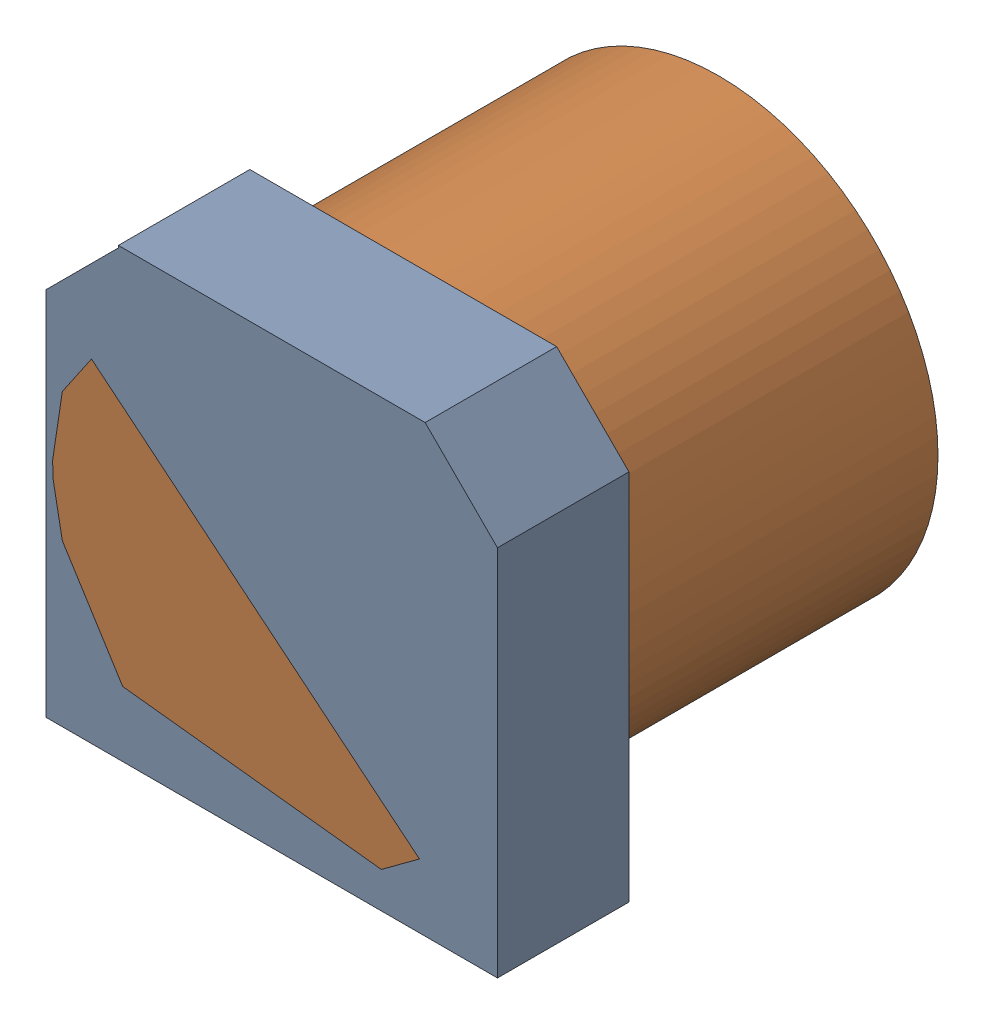
SolidWorks assembly C16, configuration Default. Lengths in mm.
Overall size (10.3 10.15 10.2).
4 component instances, 2 part files, 0 mates.
Components (placement in the parent):
- 402660496-1: 402660496 [Default] at (48.768 65.457 -4.1024) size (10.3 10.15 3)
  - Extruded_10-1: Extruded_10 [Default] at origin size (10.3 10.15 3)
- 405594336-1: 405594336 [Default] at (48.7681 65.5319 -1.1024) x (1 0 0) z (0 0 -1) size (10 10 10.2)
  - Cylinder-1: Cylinder [Default] at origin size (10 10 10.2)
